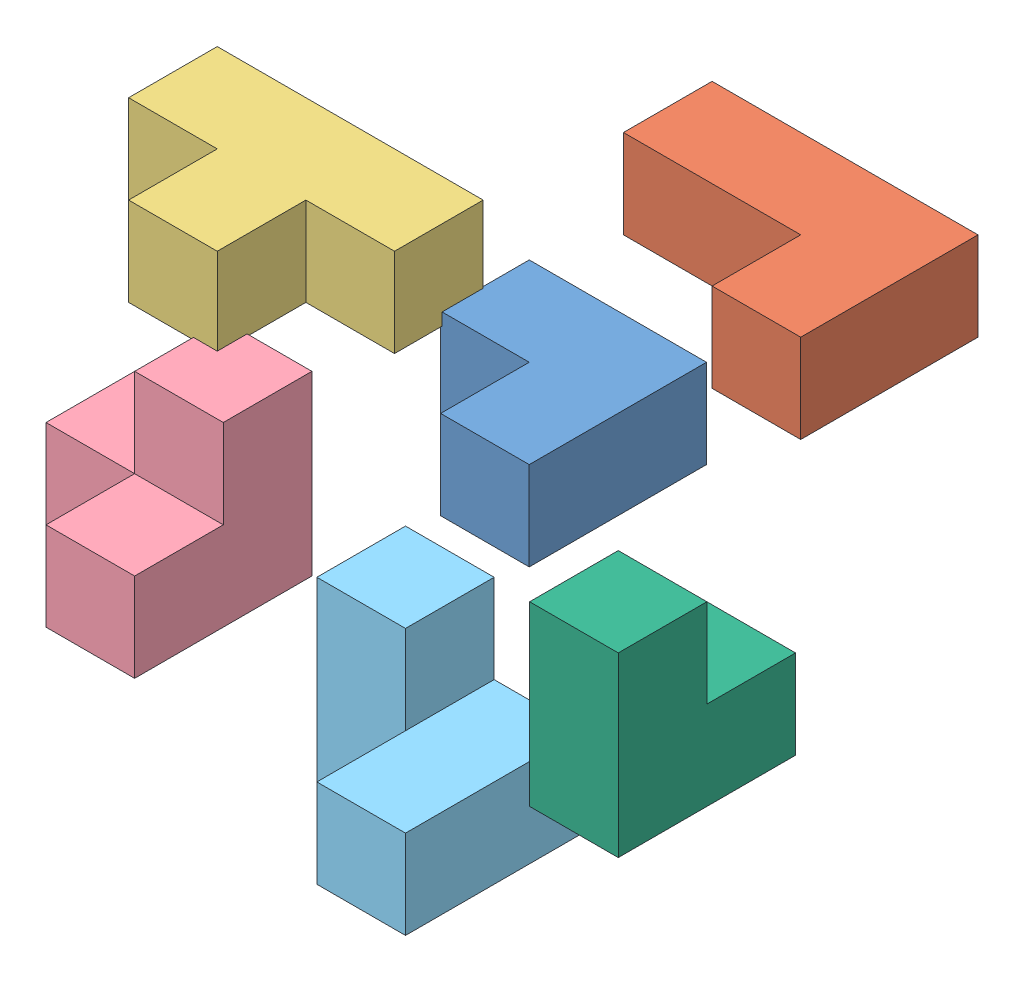
SolidWorks assembly DE_SOMA cube A00, configuration Default. Lengths in mm.
Overall size (171.15 133.48 145.48).
6 component instances, 6 part files, 0 mates.
Components (placement in the parent):
- DE_SOMA 01 L1-1: DE_SOMA 01 L1 [Default] at (10.6561 25.1028 44.3326) size (50.8 25.4 50.8)
- DE_SOMA 02 L2-1: DE_SOMA 02 L2 [Default] at (36.9544 56.8239 5.5359) size (76.2 25.4 50.8)
- DE_SOMA 03 Tee-1: DE_SOMA 03 Tee [Default] at (-52.4123 46.9874 57.9698) size (76.2 25.4 50.8)
- DE_SOMA 04 Cap-1: DE_SOMA 04 Cap [Default] at (-46.5421 -3.2058 100.214) size (50.8 50.8 50.8)
- DE_SOMA 05 sister1-1: DE_SOMA 05 sister1 [Default] at (8.0204 -51.2567 77.1588) size (50.8 50.8 50.8)
- DE_SOMA 06 sister2-1: DE_SOMA 06 sister2 [Default] at (55.2425 -15.1995 63.4095) size (50.8 50.8 50.8)
